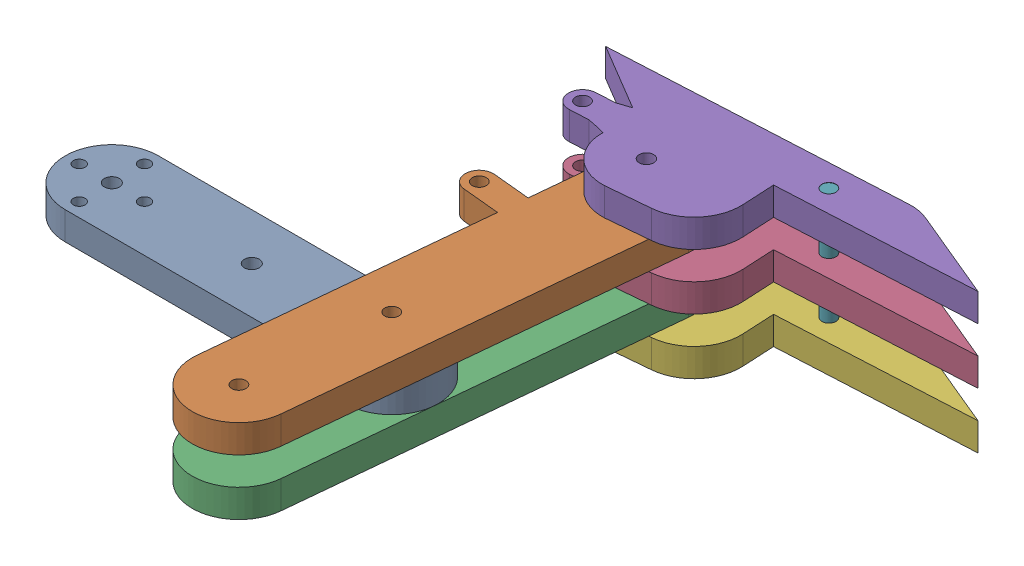
SolidWorks assembly Leg gen B, configuration Default. Lengths in mm.
Overall size (135.92 30.04 111.43).
7 component instances, 4 part files, 12 mates.
Components (placement in the parent):
- Part1-1: Part1 [Default] at (33.2096 14.7972 -3.7848) size (80 6 20)
- Part4-2: Part4 [Default] at (40.2573 26.7972 17.0426) x (-0.096843 0 0.9953) z (0.9953 0 0.096843) size (100 6 31)
- Part4-3: Part4 [Default] at (40.2573 14.7972 17.0426) x (-0.096843 0 0.9953) z (0.9953 0 0.096843) size (100 6 31)
- Part6-2: Part6 [Default] at (28.3273 14.7972 -70.8219) x (-0.998655 0 0.051848) z (-0.051848 0 -0.998655) size (85 6 27.27)
- Part6-3: Part6 [Default] at (28.3273 26.7972 -70.8219) x (-0.998655 0 0.051848) z (-0.051848 0 -0.998655) size (85 6 27.27)
- Part6-4: Part6 [Default] at (28.3273 2.7972 -70.8219) x (-0.998655 0 0.051848) z (-0.051848 0 -0.998655) size (85 6 27.27)
- leg7-1: leg7 [Default] at (63.0848 2.7571 -77.6332) x (0.996326 0 -0.085638) z (0.085638 0 0.996326) size (3 30 3)
Mates (geometry in assembly coordinates):
- Concentric2: concentric aligned: cylinder of Part1-1 through (33.2096 20.7972 -13.7848) axis (0 -1 0) radius 1.6; circle of Part4-2
- Concentric3: concentric anti-aligned: cylinder of Part1-1 through (33.2096 20.7972 -13.7848) axis (0 -1 0) radius 1.6; cylinder of Part4-3 through (33.2096 8.7972 -13.7848) axis (0 1 0) radius 1.5
- Concentric4: concentric anti-aligned: cylinder of Part4-2 through (38.0518 20.7972 -63.5498) axis (0 1 0) radius 1.5; cylinder of Part6-2 through (38.0518 20.7972 -63.5498) axis (0 -1 0) radius 1.55
- Coincident4: coincident anti-aligned: plane of Part4-2 through (30.3043 20.7972 16.0742) normal (0 -1 0); plane of Part6-2 through (28.3273 20.7972 -70.8219) normal (0 1 0)
- Coincident5: coincident anti-aligned: plane of Part1-1 through (33.2096 14.7972 -13.7848) normal (0 -1 0); plane of Part4-3 through (30.3043 14.7972 16.0742) normal (0 1 0)
- Concentric5: concentric anti-aligned: cylinder of Part4-2 through (38.0518 20.7972 -63.5498) axis (0 1 0) radius 1.5; cylinder of Part6-3 through (38.0518 32.7972 -63.5498) axis (0 -1 0) radius 1.55
- Coincident7: coincident anti-aligned: plane of Part4-3 through (30.3043 8.7972 16.0742) normal (0 -1 0); plane of Part6-4 through (28.3273 8.7972 -70.8219) normal (0 1 0)
- Concentric6: concentric anti-aligned: cylinder of Part4-3 through (38.0518 8.7972 -63.5498) axis (0 1 0) radius 1.5; cylinder of Part6-4 through (38.0518 8.7972 -63.5498) axis (0 -1 0) radius 1.55
- Coincident8: coincident aligned: plane of Part4-2 through (30.3043 26.7972 16.0742) normal (0 1 0); circle of Part6-3
- Concentric8: concentric aligned: cylinder of Part6-4 through (63.0848 8.7972 -77.6332) axis (0 -1 0) radius 1.5; cylinder of leg7-1 through (63.0848 32.7571 -77.6332) axis (0 -1 0) radius 1.5
- Concentric9: concentric aligned: cylinder of Part6-2 through (63.0848 20.7972 -77.6332) axis (0 -1 0) radius 1.5; cylinder of leg7-1 through (63.0848 32.7571 -77.6332) axis (0 -1 0) radius 1.5
- Coincident13: coincident anti-aligned: circle of Part6-3; cylinder of leg7-1 through (63.0848 32.7571 -77.6332) axis (0 -1 0) radius 1.5
